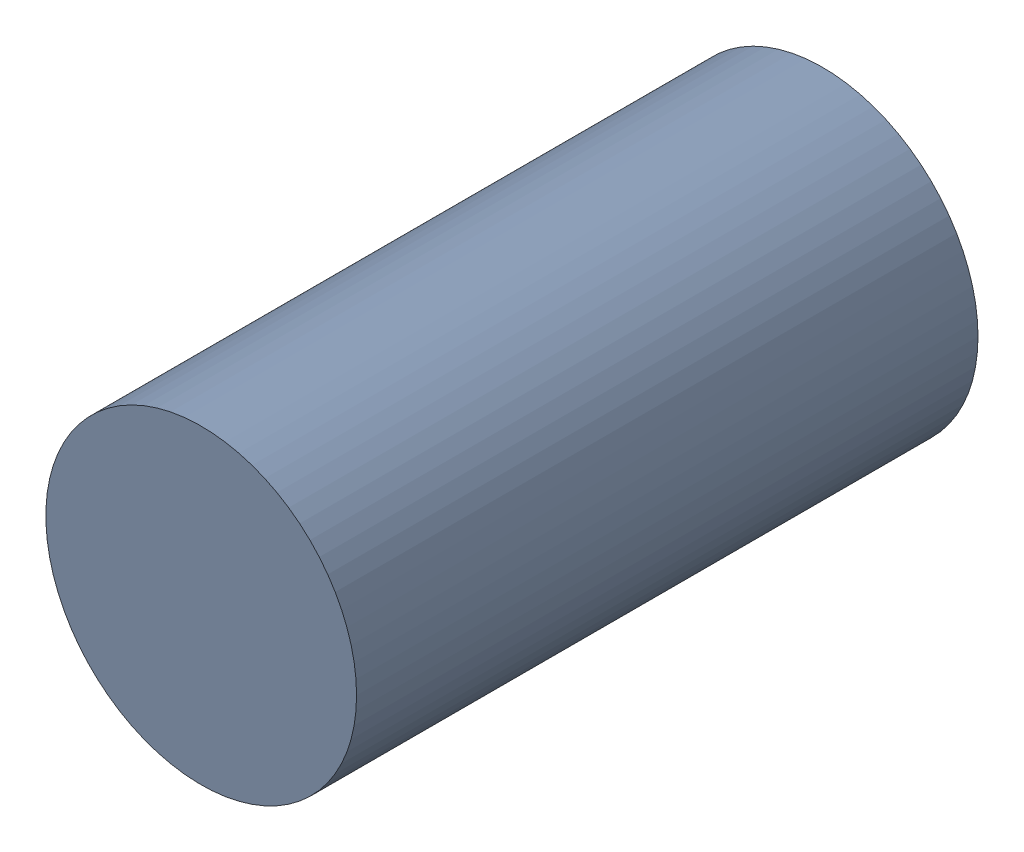
SolidWorks assembly MH10, configuration Default. Lengths in mm.
Overall size (1 1 2).
2 component instances, 1 part files, 0 mates.
Components (placement in the parent):
- 9228463120-1: 9228463120 [Default] at (80.979 80.6107 -1.5) size (1 1 2)
  - Cylinder-1: Cylinder [Default] at origin size (1 1 2)
